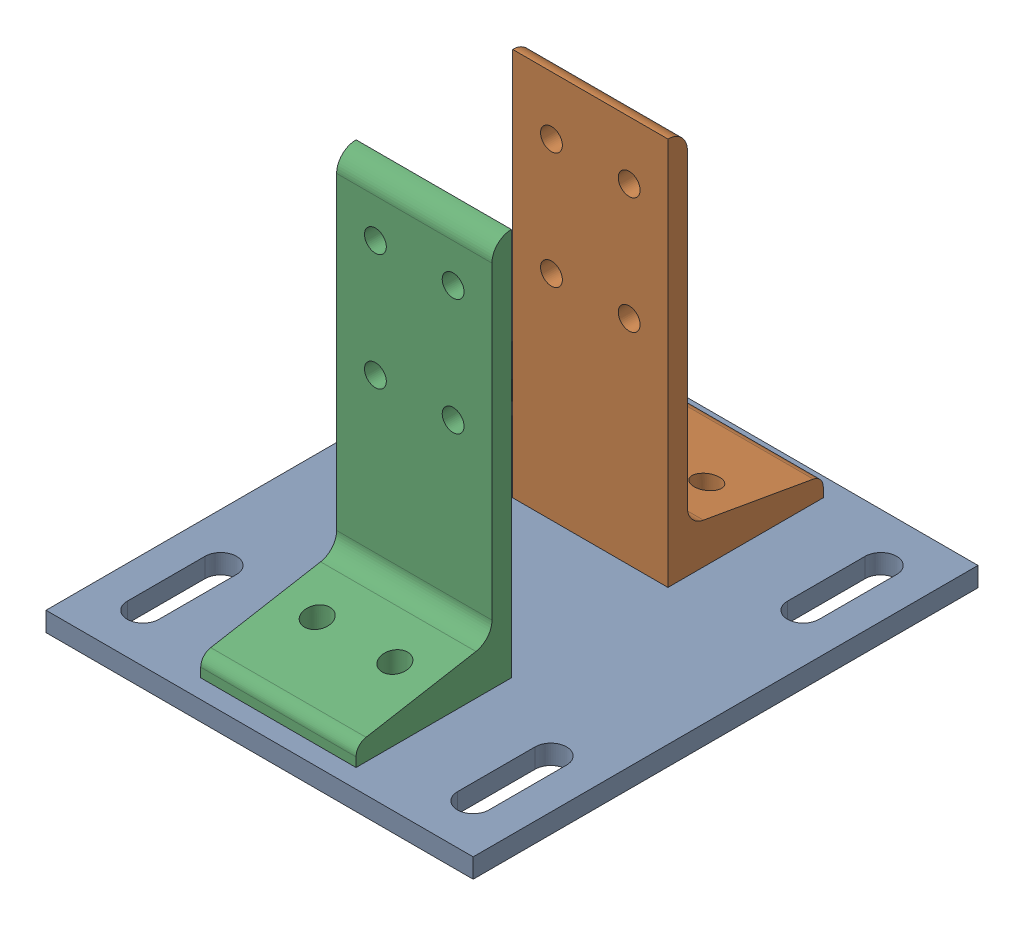
SolidWorks assembly Mirror8020-2387-DEFAULT4, configuration Default. Lengths in mm.
Overall size (139.7 133.35 165.1).
3 component instances, 2 part files, 0 mates.
Components (placement in the parent):
- Mirror8020-2387-DEFAULT_238708-1: Mirror8020-2387-DEFAULT_238708 [Default] at (-67.1549 7.3704 -27.8119) size (139.7 6.35 165.1)
- Mirror8020-2387-DEFAULT_238509-1: Mirror8020-2387-DEFAULT_238509 [Default] at (9.1264 0.0214 -49.7635) x (0 0 -1) z (1 0 0) size (50.8 127 50.8)
- Mirror8020-2387-DEFAULT_238509-2: Mirror8020-2387-DEFAULT_238509 [Default] at (-41.6736 0.0214 46.9187) x (0 0 1) z (-1 0 0) size (50.8 127 50.8)
